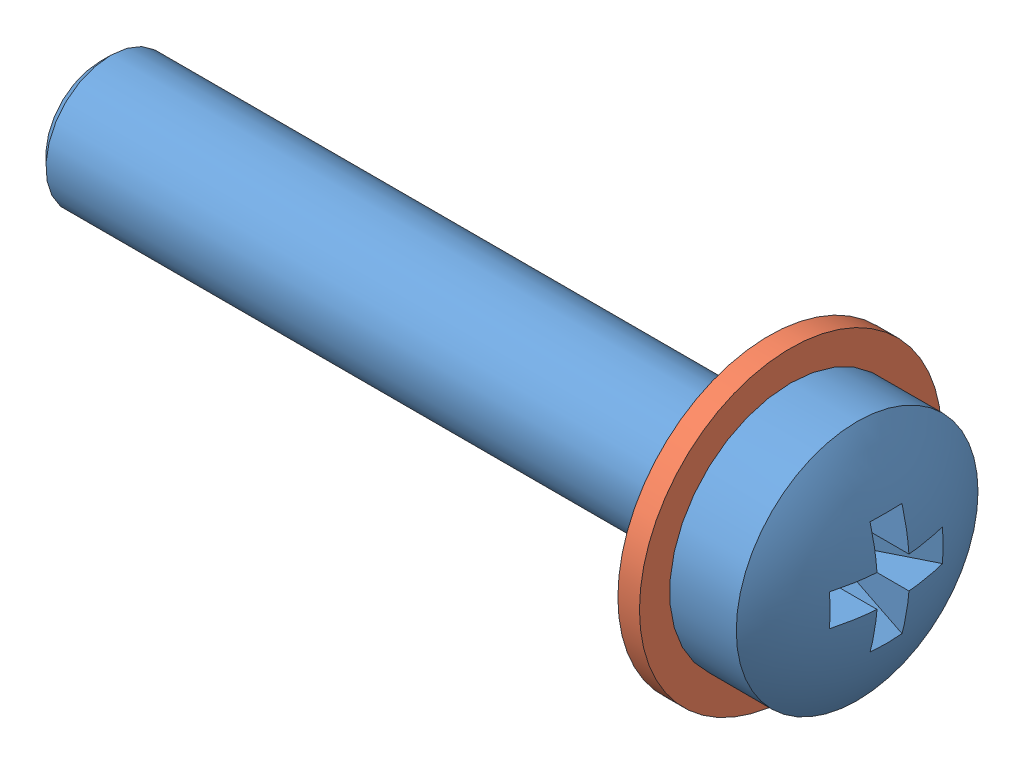
SolidWorks assembly Assembly Screw DIN 7985 - M3 x 16 --- 16N + Washer DIN 125A - M3, configuration Valor predeterminado. Lengths in mm.
Overall size (18.37 7 7).
2 component instances, 2 part files, 2 mates.
Components (placement in the parent):
- Screw DIN 7985 - M3 x 16 --- 16N-1: Screw DIN 7985 - M3 x 16 --- 16N [Valor predeterminado] at (6.2909 0.1077 18.3725) size (18.37 5.6 5.6)
- Washer DIN 125A - M3-1: Washer DIN 125A - M3 [Valor predeterminado] at (3.3909 0.1077 18.3725) size (0.5 7 7)
Mates (geometry in assembly coordinates):
- Concêntrico1: concentric: cylinder of assembly; cylinder of assembly; cylinder of Screw DIN 7985 - M3 x 16 --- 16N-1 through (6.2909 0.1077 18.3725) axis (1 0 0) radius 1.5; cylinder of Washer DIN 125A - M3-1 through (3.8909 0.1077 18.3725) axis (-1 0 0) radius 1.6
- Coincidente1: coincident: plane of assembly; plane of assembly; plane of Screw DIN 7985 - M3 x 16 --- 16N-1 through (3.8909 1.6077 18.3725) normal (-1 0 0); plane of Washer DIN 125A - M3-1 through (3.8909 0.1077 18.3725) normal (1 0 0)
